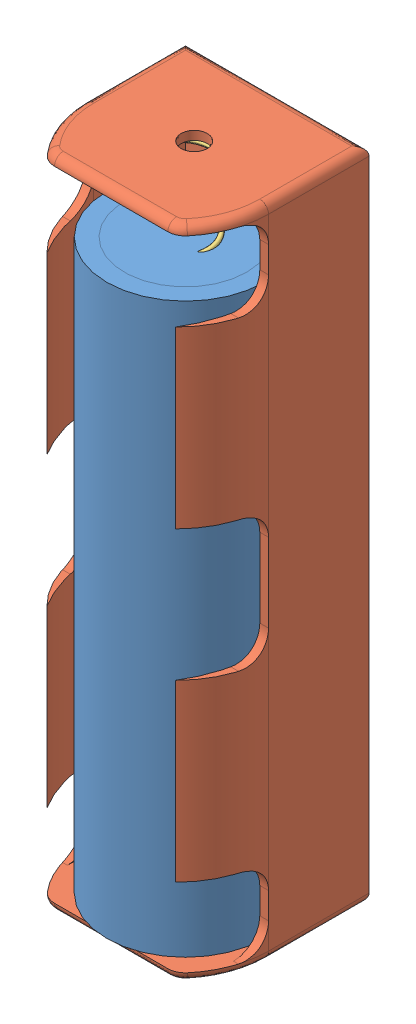
SolidWorks assembly 18650 Battery Holder v5, configuration Default. Lengths in mm.
Overall size (21 75 19.5).
5 component instances, 4 part files, 0 mates.
Components (placement in the parent):
- 18650 Battery Holder v5.step-1: 18650 Battery Holder v5.step [Default] at origin size (21 75 19.5)
  - 35v 18650.step-1: 35v 18650.step [Default] at (0 28.5 10.5) x (0 -1 0) z (0 0 1) size (65 18 18)
  - 18650 Battery Holder.step-1: 18650 Battery Holder.step [Default] at origin size (21 75 19)
  - 18650 Battery Holder-0.step-1: 18650 Battery Holder-0.step [Default] at origin size (6.94 14.73 6.96)
  - 18650 Battery Holder-1.step-1: 18650 Battery Holder-1.step [Default] at origin size (3.5 0.5 3.5)
